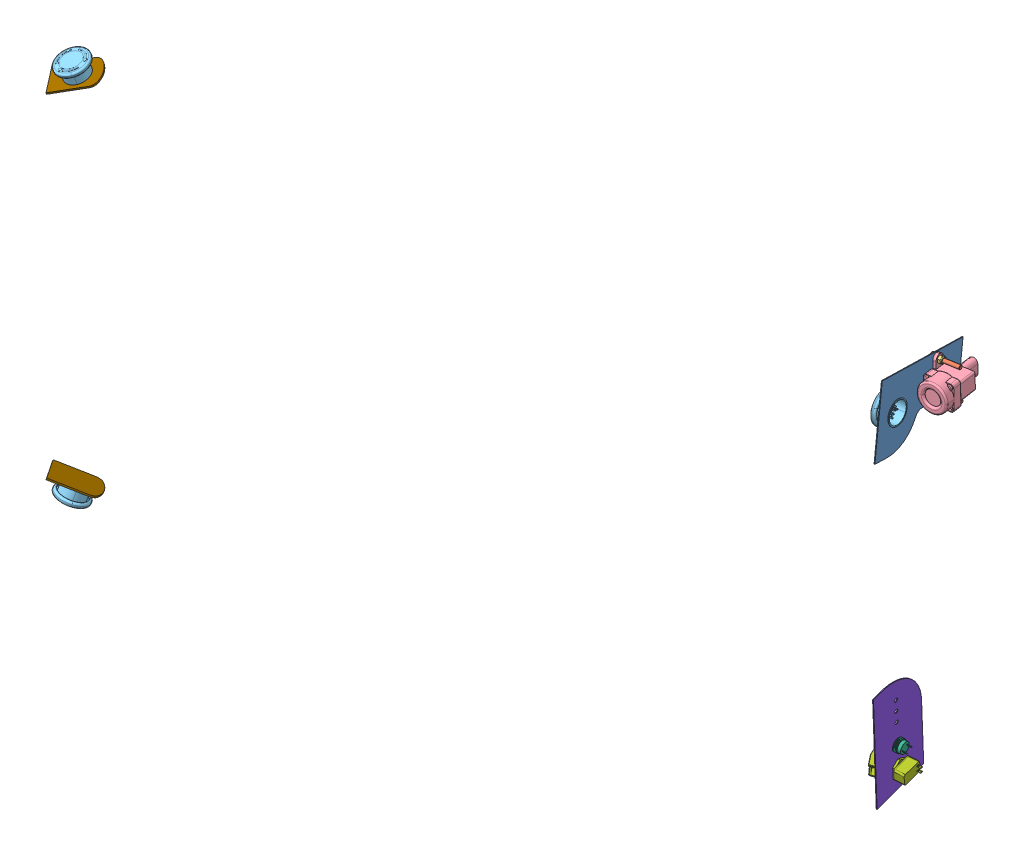
SolidWorks assembly PUTM-G-MS-Assembly, configuration Domyślna. Lengths in mm.
Overall size (984.75 531.06 333.27).
15 component instances, 9 part files, 0 mates.
Components (placement in the parent):
- PUTM-G-MS-Kill-Inertia-1: PUTM-G-MS-Kill-Inertia [Domyślna] at (-162.4803 251.7381 577.9822) x (0.043492 -0.987002 0.154708) z (-0.989561 -0.021263 0.142538) size (90 130 1)
- PUTM-FT-FABORY_ISO912_M4x10-1: PUTM-FT-FABORY_ISO912_M4x10 [M5x30 [07071.050.030]] at (-179.4099 190.5139 493.4107) x (-0.989561 -0.021263 0.142538) z (-0.06548 -0.814732 -0.576128) size (35 8.5 8.5)
- PUTM-FT-FABORY_DIN985-1: PUTM-FT-FABORY_DIN985 [M5 [12348.050.001]] at (-169.7122 190.7223 492.0139) x (-0.053914 0.971857 -0.229317) z (0.989561 0.021263 -0.142538) size (9.51 8.27 5.13)
- PUTM-FT-FABORY_ISO912_M4x10-2: PUTM-FT-FABORY_ISO912_M4x10 [M5x30 [07071.050.030]] at (-180.2518 230.5049 493.532) x (-0.989561 -0.021263 0.142538) z (0.047562 -0.981825 0.18373) size (35 8.5 8.5)
- PUTM-FT-FABORY_DIN985-2: PUTM-FT-FABORY_DIN985 [M5 [12348.050.001]] at (-170.5541 230.7133 492.1351) x (-0.014443 0.998708 0.048714) z (0.989561 0.021263 -0.142538) size (9.51 8.27 5.13)
- PUTM-G-EB-Inertia-1: PUTM-G-EB-Inertia [Default] at (-152.2706 211.0633 502.1306) x (0.021046 -0.999774 -0.003031) z (-0.989561 -0.021263 0.142538) size (52 66.6 38.3)
- PUTM-G-EB-Shutdown-Button-Cockpit-1: PUTM-G-EB-Shutdown-Button-Cockpit [Domyślna] at (-163.9222 202.5598 555.5112) x (-0.085495 0.88283 -0.461847) z (0.116017 0.469212 0.875432) size (40 19.18 40)
- PUTM-G-DS-Right-Plate-Ass-1: PUTM-G-DS-Right-Plate-Ass [Domyślna] at origin size (61.76 159.52 95.15)
  - PUTM-G-DS-Button_Drucktaster R13-507 rot v7-1: PUTM-G-DS-Button_Drucktaster R13-507 rot v7 [Domyślna] at (-158.537 -189.6343 551.3633) x (0.08944 -0.49464 0.864483) z (-0.984217 0.089177 0.152853) size (22.86 21.44 24.86)
  - PUTM-G-DS-Toggle Switch-1: PUTM-G-DS-Toggle Switch [Domyślna] at (-171.7437 -218.2883 548.4654) x (-0.137396 0.159292 -0.977624) z (0.11153 0.983196 0.144525) size (51.99 53.27 19.63)
  - PUTM-G-DS-Right_plate_leds-1: PUTM-G-DS-Right_plate_leds [Domyślna] at (-169.2965 -253.4485 578.1936) x (-0.11153 -0.983196 -0.144525) z (-0.984217 0.089177 0.152853) size (150 75 1)
- PUTM-G-EB-Kill-Switch-Mounting-Right-1: PUTM-G-EB-Kill-Switch-Mounting-Right [Domyślna] at (-1089.4652 -232.5949 756.4784) x (-0.985223 0.148262 -0.085751) z (-0.035483 0.313117 0.949051) size (62.9 2 60.64)
- PUTM-G-EB-Shutdown-Button-Cockpit-2: PUTM-G-EB-Shutdown-Button-Cockpit [Domyślna] at (-1079.1678 -238.774 749.6486) x (-0.707152 0.328674 0.626027) z (0.686921 0.109533 0.718431) size (40 19.18 40)
- PUTM-G-EB-Kill-Switch-Mounting-Right-2: PUTM-G-EB-Kill-Switch-Mounting-Right [Domyślna] at (-1089.8003 234.471 757.0849) x (-0.985223 -0.148262 -0.085751) z (-0.035483 -0.313117 0.949051) size (62.9 2 60.64)
- PUTM-G-EB-Shutdown-Button-Cockpit-3: PUTM-G-EB-Shutdown-Button-Cockpit [Domyślna] at (-1079.1678 238.774 749.6486) x (0.707152 0.328674 -0.626027) z (0.686921 -0.109533 0.718431) size (40 19.18 40)
